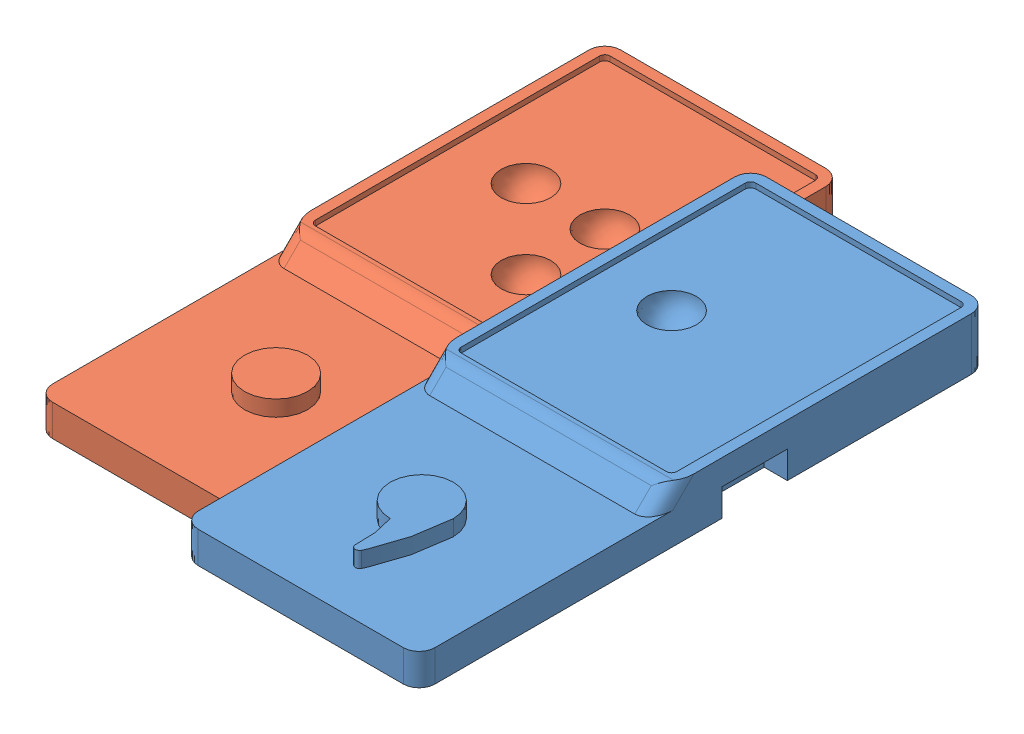
SolidWorks assembly punct-assembly, configuration По умолчанию. Lengths in mm.
Overall size (46.48 11.6 64.13).
2 component instances, 2 part files, 0 mates.
Components (placement in the parent):
- comma-1: comma [По умолчанию] at origin size (22.5 5 54)
- dot-1: dot [По умолчанию] at (-23.9765 -6.5952 -10.1298) size (22.5 5 54)
